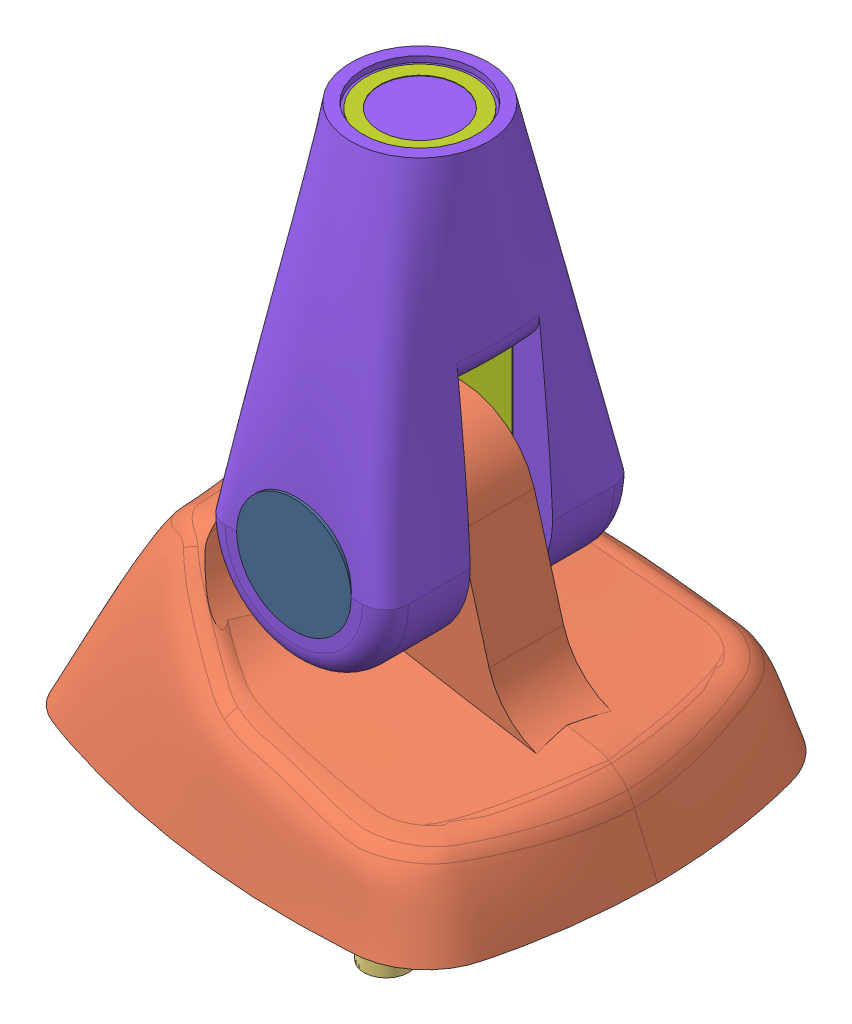
SolidWorks assembly Assem, configuration Default. Lengths in mm.
Overall size (42.09 66.5 37.33).
12 component instances, 11 part files, 14 mates.
Components (placement in the parent):
- base metal-1: base metal [Default] at (-19.3424 -0.4283 1.3444) size (26 19.8 16.8)
- base_plastic_4-1: base_plastic_4 [Default] at (1897.0017 -6209.6505 23.1132) x (-1 0 0) z (0 -1 0) size (42533.26 37922.71 43425.84)
- Screw-1: Screw [Default] at (-19.3276 1.1717 1.3444) x (0.874553 0 0.484931) z (-0.484931 0 0.874553) size (10.39 25.7 9)
- ThinMetalWasher-1: ThinMetalWasher [Default] at (-16.2424 13.8717 3.5944) size (11 11 1)
- ThickMetalWasher-1: ThickMetalWasher [Default] at (-16.2424 13.8717 -2.0056) size (11 11 1.1)
- Up Assem-1: Up Assem [Default] at (-16.2059 -27.5657 27.5258) x (1 0 0) z (0 -1 0) size (21.49 22.29 37.5)
  - screw pin-1: screw pin [Default] at (-0.0364 -18.6813 -41.4374) size (7.4 17.79 7.4)
  - top metal-1: top metal [Default] at (-0.0364 -26.0313 -70.4903) x (1 0 0) z (0 -1 0) size (12.6 35.35 14.68)
  - upper part2-1: upper part2 [Default] at (-0.0364 -26.0313 -70.9374) x (0 1 0) z (1 0 0) size (22.29 37.5 21.49)
  - screw pin washer-1: screw pin washer [Default] at (-0.0364 -22.4313 -41.4374) x (0 0 1) z (-1 0 0) size (8.08 3.75 7)
  - screw cover-1: screw cover [Default] at (-0.0364 -19.0313 -41.4374) size (10 4 10)
- washer-1: washer [Default] at (-19.3276 -0.5158 1.3444) x (0 0 1) z (1 0 0) size (21 4 21)
Mates (geometry in assembly coordinates):
- Concentric1: concentric anti-aligned: cylinder of base metal-1 through (-16.2424 13.8717 3.5944) axis (0 0 -1) radius 2.575; cylinder of base_plastic_4-1 through (-16.2424 13.8717 -1.9056) axis (0 0 1) radius 5.6
- Distance2: distance = 1 mm aligned: plane of base_plastic_4-1 through (-15.3768 -4.0158 4.5944) normal (0 0 1); plane of base metal-1 through (-19.3424 -0.4283 3.5944) normal (0 0 1)
- Concentric3: concentric aligned: cylinder of base_plastic_4-1 through (-19.3276 -8.0158 1.3444) axis (0 1 0) radius 2.75; cylinder of Screw-1 through (-19.3276 -23.1283 1.3444) axis (0 1 0) radius 2.5
- Parallel1: parallel anti-aligned: plane of base metal-1 through (-14.6842 1.0217 1.2637) normal (-0.99985 0 0.017314); plane of Screw-1 through (-14.7843 2.5717 3.8636) normal (0.99985 0 -0.017314)
- Coincident3: coincident anti-aligned: plane of base metal-1 through (-19.3424 2.5717 1.3444) normal (0 -1 0); plane of Screw-1 through (-19.3276 2.5717 1.3444) normal (0 1 0)
- Concentric4: concentric aligned: cylinder of base metal-1 through (-16.2424 13.8717 3.5944) axis (0 0 -1) radius 2.575; cylinder of ThickMetalWasher-1 through (-16.2424 13.8717 -0.9056) axis (0 0 -1) radius 2.6
- Coincident4: coincident anti-aligned: plane of base metal-1 through (-19.3424 -0.4283 -0.9056) normal (0 0 -1); plane of ThickMetalWasher-1 through (-16.2424 13.8717 -0.9056) normal (0 0 1)
- Concentric5: concentric anti-aligned: cylinder of base metal-1 through (-16.2424 13.8717 3.5944) axis (0 0 -1) radius 2.575; circle of ThinMetalWasher-1
- Coincident5: coincident anti-aligned: plane of base metal-1 through (-19.3424 -0.4283 3.5944) normal (0 0 1); plane of ThinMetalWasher-1 through (-16.2424 13.8717 3.5944) normal (0 0 -1)
- Concentric6: concentric anti-aligned: cylinder of base metal-1 through (-16.2424 13.8717 3.5944) axis (0 0 -1) radius 2.575; cylinder of Up Assem-1/screw pin-1 through (-16.2424 13.8717 -6.1556) axis (0 0 1) radius 2.45
- Coincident6: coincident anti-aligned: plane of Up Assem-1/top metal-1 through (-16.2424 42.9246 -2.0056) normal (0 0 1); plane of ThickMetalWasher-1 through (-16.2424 13.8717 -2.0056) normal (0 0 -1)
- Coincident7: coincident anti-aligned: plane of base_plastic_4-1 through (-15.3768 -0.5158 1.3444) normal (0 -1 0); plane of washer-1 through (-51.9212 -0.5158 1.3444) normal (0 1 0)
- Parallel3: parallel aligned: plane of base metal-1 through (-19.3424 -0.4283 1.3444) normal (0 0 1); plane of washer-1
- Concentric10: concentric aligned: cylinder of base_plastic_4-1 through (-19.3276 -3.5158 1.3444) axis (0 1 0) radius 6.225; cylinder of washer-1 through (-19.3276 -17.2731 1.3444) axis (0 1 0) radius 3.65
